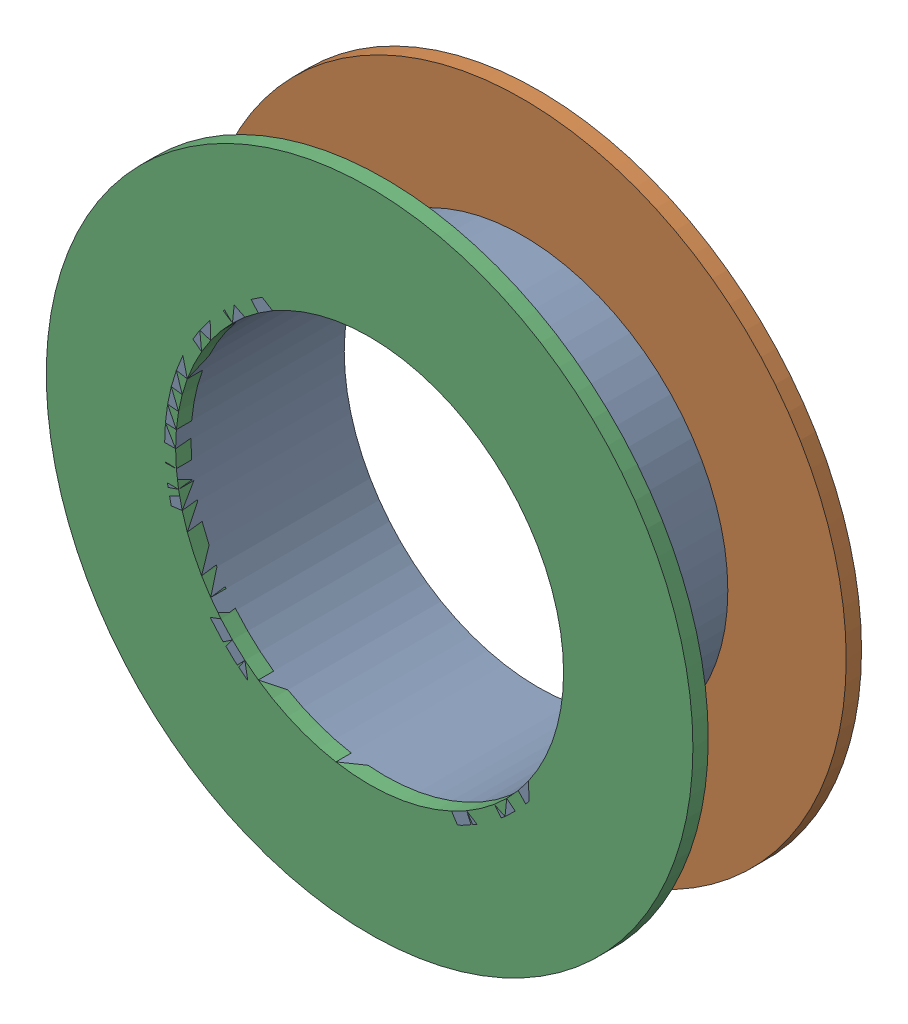
SolidWorks assembly Pad UART-3(18.08mm,43.4mm) on Multi-Layer, configuration Predeterminado. Lengths in mm.
Overall size (1.5 1.5 0.39).
6 component instances, 2 part files, 0 mates.
Components (placement in the parent):
- Pad Hole-1-1: Pad Hole-1 [Predeterminado] at (18.08 43.4 -0.4013) size (0.95 0.95 0.39)
  - Pad Hole-Part-1-1-1: Pad Hole-Part-1-1 [Predeterminado] at origin size (0.95 0.95 0.39)
- Top Layer-1-1: Top Layer-1 [Predeterminado] at (18.08 43.4 -0.4013) size (1.5 1.5 0.04)
  - Top Layer-Part-1-1-1: Top Layer-Part-1-1 [Predeterminado] at origin size (1.5 1.5 0.04)
- Top Layer-1-2: Top Layer-1 [Predeterminado] at (18.08 43.4 -0.0457) size (1.5 1.5 0.04)
  - Top Layer-Part-1-1-1: Top Layer-Part-1-1 [Predeterminado] at origin size (1.5 1.5 0.04)
